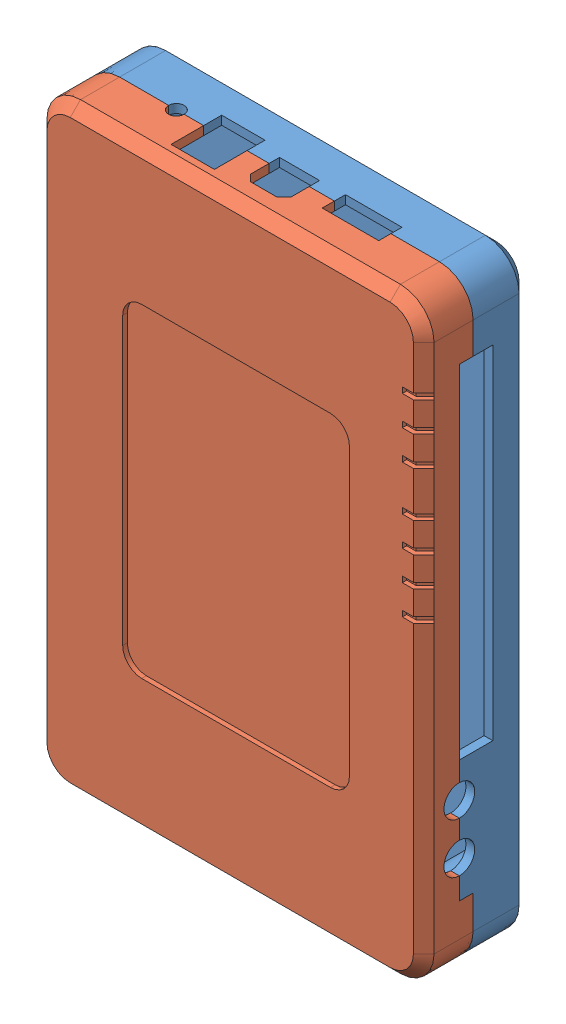
SolidWorks assembly myRIO, configuration 預設. Lengths in mm.
Overall size (88.6 136.6 24.18).
2 component instances, 2 part files, 6 mates.
Components (placement in the parent):
- myRIO Bottom-1: myRIO Bottom [預設] at (0 0 12.88) x (-1 0 0) z (0 0 -1) size (88.6 136.6 16.04)
- myRIO Top-1: myRIO Top [預設] at (0 0 12.88) size (88.6 136.6 11.3)
Mates (geometry in assembly coordinates):
- 重合/共線/共點1: coincident anti-aligned: plane of myRIO Bottom-1 through (36.6 60.6 12.88) normal (0 0 1); plane of myRIO Top-1 through (-36.6 60.6 12.88) normal (0 0 -1)
- 重合/共線/共點2: coincident aligned: plane of myRIO Bottom-1 through (44.3 60.6 0) normal (1 0 0); plane of myRIO Top-1 through (44.3 60.6 24.18) normal (1 0 0)
- 重合/共線/共點3: coincident aligned: plane of myRIO Bottom-1 through (-36.6 68.3 0) normal (0 1 0); plane of myRIO Top-1 through (-36.6 68.3 24.18) normal (0 1 0)
- 相互對稱1: symmetric aligned: plane of myRIO Bottom-1 through (-44.3 -60.6 0) normal (-1 0 0); plane of myRIO Bottom-1 through (44.3 60.6 0) normal (1 0 0); plane of assembly through (0 0 0) normal (1 0 0)
- 重合/共線/共點5: coincident anti-aligned: plane of myRIO Bottom-1 through (36.6 60.6 0) normal (0 0 -1); plane of assembly through (0 0 0) normal (0 0 1)
- 相互對稱4: symmetric aligned: plane of myRIO Bottom-1 through (-36.6 68.3 0) normal (0 1 0); plane of myRIO Bottom-1 through (36.6 -68.3 0) normal (0 -1 0); plane of assembly through (0 0 0) normal (0 1 0)
